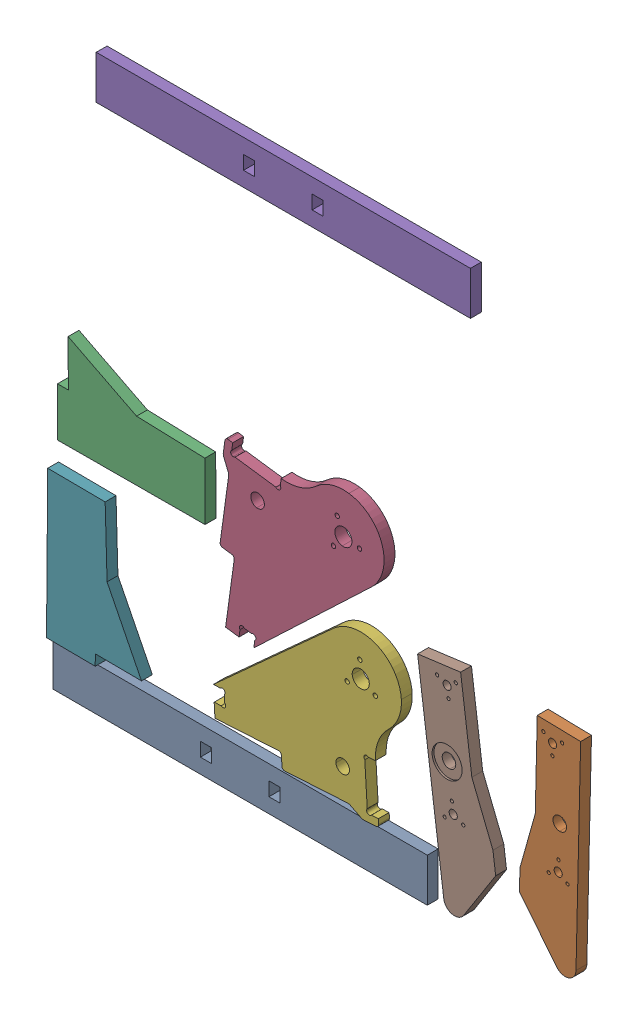
SolidWorks assembly Frame stock layout, configuration Default. Lengths in mm.
Overall size (1524 670.22 31.75).
8 component instances, 4 part files, 7 mates.
Components (placement in the parent):
- Back-1: Back [Default] at (230.0382 37.9417 19.05) size (438.15 50.8 12.7)
- drive-1: drive [Default] at (595.7916 242.9893 -219.075) x (0 0 1) z (-0.023159 -0.999732 0) size (12.7 67.24 247.65)
- front-1: front [Default] at (-17.5828 293.0134 -158.75) x (0.999993 0.003798 0) z (0 0 1) size (172.58 111.12 12.7)
- inner-1: inner [Default] at (232.0451 198.8611 -46.5) x (0 0 1) z (0.135127 0.990828 0) size (12.7 188.91 225.43)
- Back-2: Back [Default] at (274.2054 651.8076 12.7) size (438.15 50.8 12.7)
- inner-2: inner [Default] at (244.0182 100.3257 46.5) x (0 0 -1) z (0.998241 0.059293 0) size (12.7 188.91 225.43)
- front-2: front [Default] at (48.1013 32.5583 158.75) x (0.008208 0.999966 0) z (0 0 -1) size (172.58 111.12 12.7)
- drive-2: drive [Default] at (485.0163 252.7792 219.075) x (0 0 -1) z (0.130484 -0.99145 0) size (12.7 67.24 247.65)
Mates (geometry in assembly coordinates):
- Coincident1: coincident aligned: plane of Back-1 through (230.0382 37.9417 0) normal (0 0 1)
- Coincident2: coincident aligned: plane of Back-1 through (230.0382 37.9417 0) normal (0 0 1); plane of drive-1 through (595.7916 242.9893 0) normal (0 0 1)
- Coincident3: coincident aligned: plane of Back-1 through (230.0382 37.9417 0) normal (0 0 1); plane of inner-1 through (350.8756 330.0571 0) normal (0 0 1)
- Coincident4: coincident aligned: plane of Back-1 through (230.0382 37.9417 0) normal (0 0 1); plane of front-1 through (-17.5828 293.0134 0) normal (0 0 1)
- Coincident5: coincident anti-aligned: plane of Back-1 through (230.0382 37.9417 0) normal (0 0 1); plane of inner-2 through (383.8812 208.822 0) normal (0 0 -1)
- Coincident6: coincident anti-aligned: plane of Back-1 through (230.0382 37.9417 0) normal (0 0 1); plane of front-2 through (48.1013 32.5583 0) normal (0 0 -1)
- Coincident7: coincident anti-aligned: plane of drive-1 through (595.7916 242.9893 0) normal (0 0 1); plane of drive-2 through (485.0163 252.7792 0) normal (0 0 -1)
